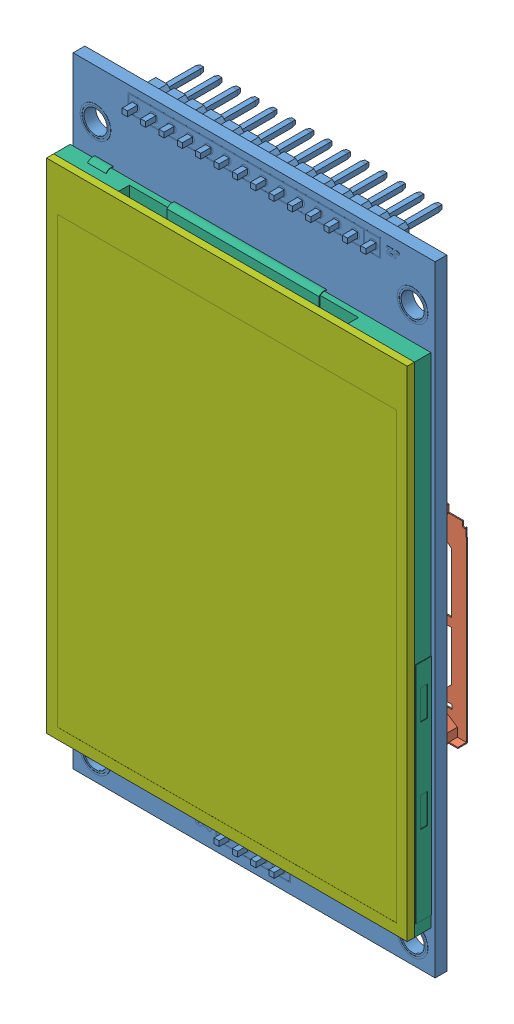
SolidWorks assembly 2.8 TFT Module_mod, configuration Default. Lengths in mm.
Overall size (50.19 85.9 12.99).
15 component instances, 7 part files, 3 mates.
Components (placement in the parent):
- 2.8 TFT Module.stp-1: 2.8 TFT Module.stp [Default] at origin size (50.19 85.9 11.99)
  - 2.8 LCD TFT Module - Without Glass.stp-1: 2.8 LCD TFT Module - Without Glass.stp [Default] at origin size (50.14 85.9 10.67)
  - 5035000993.stp-1: 5035000993.stp [Default] at (3.5564 -3.3047 -2.85) x (0 1 0) z (0 0 -1) size (28.6 21.52 2.95)
  - 0603 Resistor.stp-1: 0603 Resistor.stp [Default] at (-2.2311 -3.165 0.0025) x (-1 0 0) z (0 0 -1) size (1.6 0.85 0.56)
  - 0603 Capacitor.stp-1: 0603 Capacitor.stp [Default] at (-14.5217 25.6289 0.0025) x (1 0 0) z (0 0 -1) size (1.6 0.84 0.84)
  - 0603 Capacitor.stp-2: 0603 Capacitor.stp [Default] at (-2.484 19.738 0.0025) x (-1 0 0) z (0 0 -1) size (1.6 0.84 0.84)
  - 0603 Resistor.stp-2: 0603 Resistor.stp [Default] at (-3.8795 -4.7617 0.0025) x (1 0 0) z (0 0 -1) size (1.6 0.85 0.56)
  - 0603 Resistor.stp-3: 0603 Resistor.stp [Default] at (-2.3355 -0.9936 0.0025) x (-1 0 0) z (0 0 -1) size (1.6 0.85 0.56)
  - 0603 Resistor.stp-4: 0603 Resistor.stp [Default] at (-12.9341 26.6747 0.0025) x (-1 0 0) z (0 0 -1) size (1.6 0.85 0.56)
  - 0603 Resistor.stp-5: 0603 Resistor.stp [Default] at (4.5338 19.5922 0.0025) x (-1 0 0) z (0 0 -1) size (1.6 0.85 0.56)
  - 0603 Resistor.stp-6: 0603 Resistor.stp [Default] at (4.3803 26.5372 0.0025) x (-1 0 0) z (0 0 -1) size (1.6 0.85 0.56)
  - SOT23-3.stp-1: SOT23-3.stp [Default] at (3.6167 23.9432 0.105) x (0.003406 0.999994 0) z (0 0 -1) size (2.9 3.01 1.23)
  - SOT23-3.stp-2: SOT23-3.stp [Default] at (-3.3735 23.944 0.105) x (0.999985 -0.005499 0) z (0 0 -1) size (2.9 3.01 1.23)
  - 2.8in TFT(Without Glass)- Tucked Cable.stp-1: 2.8in TFT(Without Glass)- Tucked Cable.stp [Default] at (-0.0571 -2.2987 1.6256) x (-1 0 0) z (0 0 1) size (50.11 69.48 2.83)
- GLASS-1: GLASS [Default] at (24.922 -36.8028 4.3434) x (-1 0 0) z (0 1 0) size (49.96 1 69.01)
Mates (geometry in assembly coordinates):
- Coincident3: coincident: plane of 2.8 TFT Module.stp-1/2.8in TFT(Without Glass)- Tucked Cable.stp-1 through (-0.0571 -2.2987 4.3434) normal (0 0 1); plane of GLASS-1 through (24.922 -36.8028 4.3434) normal (0 0 -1)
- Coincident4: coincident: plane of 2.8 TFT Module.stp-1/2.8in TFT(Without Glass)- Tucked Cable.stp-1 through (-25.038 -36.8046 4.3434) normal (-1 0 0); plane of GLASS-1 through (-25.038 -36.8028 5.3434) normal (-1 0 0)
- Coincident5: coincident aligned: plane of 2.8 TFT Module.stp-1/2.8in TFT(Without Glass)- Tucked Cable.stp-1 through (-25.038 32.2072 4.3434) normal (0 1 0); plane of GLASS-1 through (24.922 32.2072 5.3434) normal (0 1 0)
